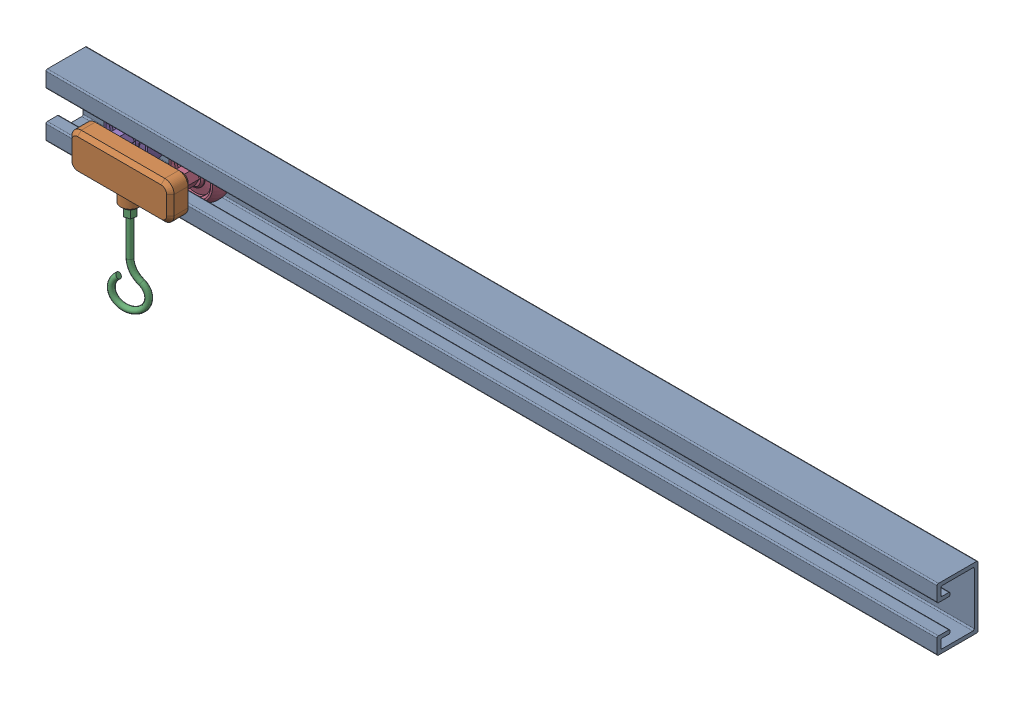
SolidWorks assembly 02_A_CSWA_Lvl9, configuration Default. Lengths in mm.
Overall size (1219.2 212.09 88.9).
5 component instances, 4 part files, 18 mates.
Components (placement in the parent):
- Base-Bracket-1: Base-Bracket [Default] at origin size (1219.2 85.09 55.88)
- Cart-1: Cart [Default] at (133.35 34.925 54.61) size (139.7 63.5 36.83)
- Hook-1: Hook [Default] at (133.35 -15.875 69.215) x (0.309017 0 0.951057) z (-0.951057 0 0.309017) size (12.7 160.65 48.26)
- Wheel-1: Wheel [Default] at (177.8 34.925 16.51) x (-1 0 0) z (0 0 1) size (69.85 69.85 64.77)
- Wheel-2: Wheel [Default] at (88.9 34.925 16.51) size (69.85 69.85 64.77)
Mates (geometry in assembly coordinates):
- Concentric1: concentric aligned: cylinder of Cart-1 through (88.9 34.925 77.47) axis (0 0 -1) radius 5.715; cylinder of Wheel-2 through (88.9 34.925 16.51) axis (0 0 -1) radius 5.08
- Coincident1: coincident aligned: circle of Cart-1; plane of Wheel-2 through (88.9 34.925 46.99) normal (0 0 1)
- Concentric2: concentric aligned: cylinder of Cart-1 through (177.8 34.925 77.47) axis (0 0 -1) radius 5.715; cylinder of Wheel-1 through (177.8 34.925 16.51) axis (0 0 -1) radius 5.08
- Concentric3: concentric aligned: cylinder of Cart-1 through (133.35 22.225 69.215) axis (0 -1 0) radius 5.08; cylinder of Hook-1 through (133.35 74.6934 69.215) axis (0 -1 0) radius 5.08
- Coincident3: coincident anti-aligned: plane of Cart-1 through (133.35 -3.175 69.215) normal (0 -1 0); plane of Hook-1 through (133.35 -3.175 69.215) normal (0 1 0)
- Parallel1: parallel aligned: plane of Cart-1 through (133.35 60.325 77.47) normal (0 1 0); plane of Wheel-1 through (183.6659 45.085 -14.4213) normal (0 1 0)
- Coincident4: coincident anti-aligned: plane of Cart-1 through (177.8 34.925 46.99) normal (0 0 -1); plane of Wheel-1 through (177.8 34.925 46.99) normal (0 0 1)
- Parallel2: parallel aligned: plane of Cart-1 through (133.35 60.325 77.47) normal (0 1 0); plane of Wheel-1 through (183.6659 45.085 -14.4213) normal (0 1 0)
- Parallel3: parallel aligned: plane of Cart-1 through (133.35 60.325 77.47) normal (0 1 0); plane of Wheel-2 through (94.7659 45.085 -14.4213) normal (0 1 0)
- Parallel4: parallel anti-aligned: plane of Base-Bracket-1 through (1219.2 57.15 45.72) normal (0 -1 0); plane of Wheel-1 through (183.6659 45.085 -14.4213) normal (0 1 0)
- Parallel5: parallel anti-aligned: plane of Base-Bracket-1 through (1219.2 57.15 45.72) normal (0 -1 0); plane of Wheel-2 through (94.7659 45.085 -14.4213) normal (0 1 0)
- Parallel6: parallel anti-aligned: plane of Base-Bracket-1 through (1219.2 74.93 50.8) normal (0 0 1); plane of Cart-1 through (133.35 34.925 54.61) normal (0 0 -1)
- Width1: width anti-aligned: plane of Base-Bracket-1 through (1219.2 17.78 33.02) normal (0 0 -1); plane of Wheel-1 through (1219.2 0 0) normal (0 0 1); plane of Base-Bracket-1 through (177.8 34.925 30.48) normal (0 0 1); plane of Wheel-1 through (177.8 34.925 2.54) normal (0 0 -1)
- Tangent1: tangent anti-aligned: plane of Base-Bracket-1 through (1219.2 0 0) normal (0 1 0); torus of Wheel-2
- Angle1: planar angle = 0.314159 rad aligned: plane of Hook-1 through (131.8255 -3.175 76.3871) normal (0.309017 0 0.951057); plane of Cart-1 through (133.35 34.925 83.82) normal (0 0 1)
- Distance3: distance = 63.5 mm aligned: plane of Cart-1 through (63.5 34.925 77.47) normal (-1 0 0); plane of Base-Bracket-1 through (0 0 0) normal (-1 0 0)
- Parallel8: parallel anti-aligned: plane of Base-Bracket-1 through (1219.2 0 50.8) normal (0 0 1); plane of Cart-1 through (133.35 34.925 54.61) normal (0 0 -1)
- Tangent2: tangent anti-aligned: plane of Base-Bracket-1 through (1219.2 0 0) normal (0 1 0); torus of Wheel-1
